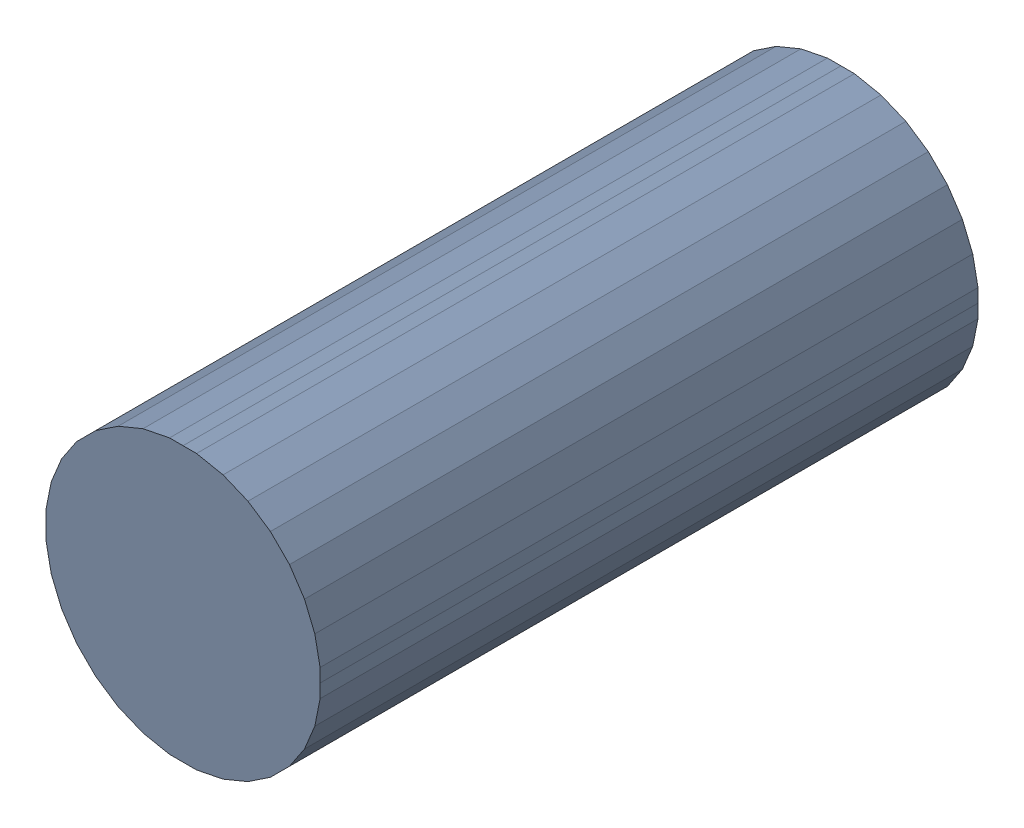
SolidWorks assembly C2.step, configuration Default. Lengths in mm.
Overall size (5 5 12).
2 component instances, 1 part files, 0 mates.
Components (placement in the parent):
- 6100339584.step-1: 6100339584.step [Default] at (6.985 37.211 0) size (5 5 12)
  - Extruded-49.step-1: Extruded-49.step [Default] at origin size (5 5 12)
